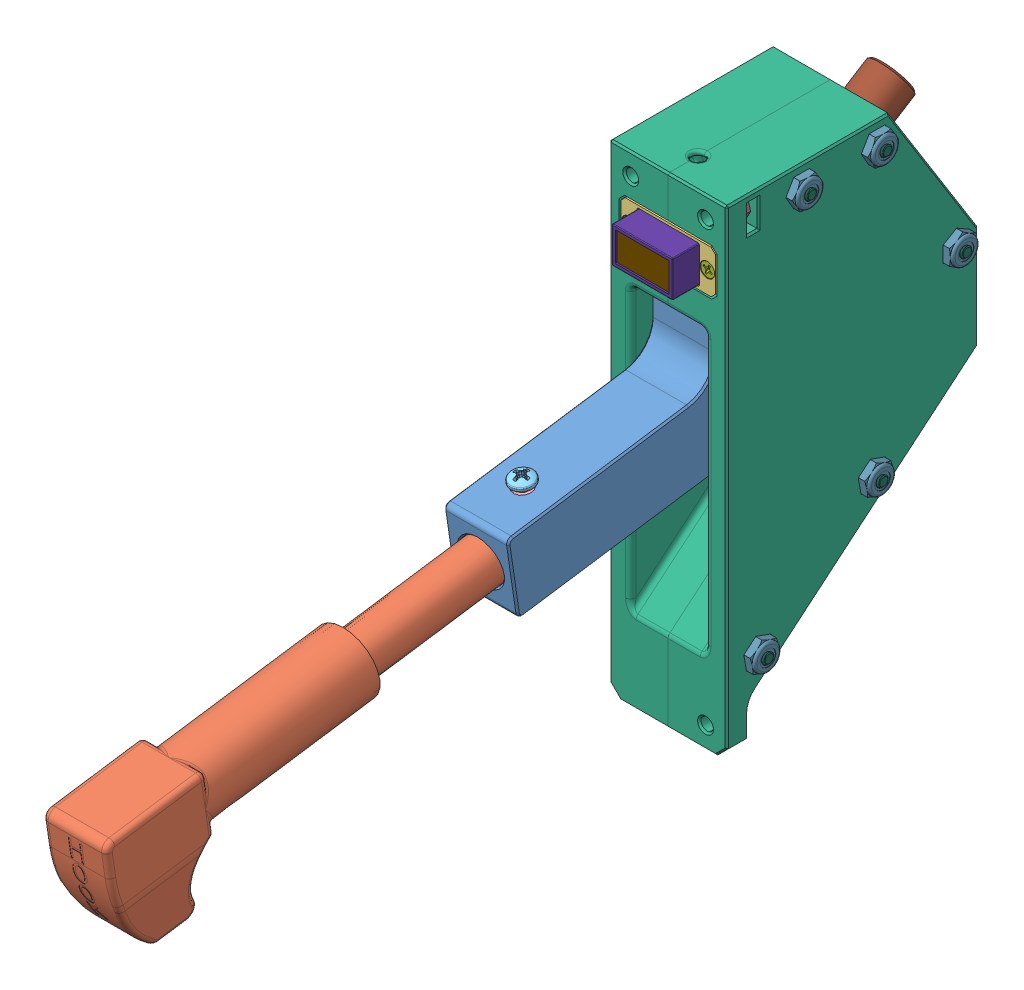
SolidWorks assembly Hook Lever Assembly, configuration UP. Lengths in mm.
Overall size (40.7 142.92 260.87).
49 component instances, 25 part files, 11 mates.
Components (placement in the parent):
- Hook Lever-1: Hook Lever [Default] at (0 -0.2029 9.2115) x (1 0 0) z (0 -0.006159 0.999981) size (22.23 101.03 219.67)
  - Hook Lever Body-1: Hook Lever Body [Default] at origin size (19.05 66.67 99.86)
  - Hook Lever Handle-1: Hook Lever Handle [Default] at (0 20.3447 1.0942) x (1 0 0) z (0 -0.139173 0.990268) size (19.43 38.29 166.69)
  - 6338K411-1: 6338K411 [Default] at (11.1125 50.8 -33.1) x (0 -1 0) z (0 0 -1) size (12.7 6.35 12.7)
  - 6338K411-2: 6338K411 [Default] at (-11.1125 50.8 -33.1) x (0 -1 0) z (0 0 1) size (12.7 6.35 12.7)
  - 93365A130-1: 93365A130 [Default] at (0 26.9745 33.7674) x (1 0 0) z (0 -0.139173 0.990268) size (5.56 3.88 5.56)
  - 91249A144-1: 91249A144 [Default] at (0 21.9439 33.0604) x (1 0 0) z (0 0.990268 0.139173) size (20.88 20.88 23.36)
- Hook Lever Chassis-1: Hook Lever Chassis [Default] at origin size (40.7 142.92 101.62)
  - Hook Lever Chassis Body-1: Hook Lever Chassis Body [Default] at origin size (34.93 142.92 75.16)
  - Hook Lever .25 Shaft -1: Hook Lever .25 Shaft  [Default] at origin size (31.75 6.35 6.35)
  - 93365A120_BRASS HEAT-SET INSERT FOR PLASTICS_4-40-1: 93365A120_BRASS HEAT-SET INSERT FOR PLASTICS_4-40 [93365A120] at (-11.1125 2.6229 -53.39) x (0 1 0) z (0 0 -1) size (4.37 3.82 4.37)
  - 93365A120_BRASS HEAT-SET INSERT FOR PLASTICS_4-40-2: 93365A120_BRASS HEAT-SET INSERT FOR PLASTICS_4-40 [93365A120] at (-11.1125 24.8048 -63.6241) x (0 -1 0) z (0 0 1) size (4.37 3.82 4.37)
  - 7779K52-1: 7779K52 [Default] at (-5.9575 13.7248 -58.4313) x (0 0.642788 -0.766044) z (1 0 0) size (37.8 27.88 10.31)
  - 91249A115-1: 91249A115 [Default] at (-16.6775 2.6447 -53.2386) x (0 -0.642788 0.766044) z (1 0 0) size (23.09 11.07 22.41)
  - 91249A115-2: 91249A115 [Default] at (-16.6775 24.8048 -63.6241) x (0 -0.642788 0.766044) z (1 0 0) size (23.09 11.07 22.41)
  - 84835A14-1: 84835A14 [Default] at (0 68.5051 -51.909) x (1 0 0) z (0 0.848048 0.529919) size (17.48 34.82 17.48)
  - 92141A029-1: 92141A029 [Default] at (-11.1887 50.8 -23.575) x (0 1 0) z (0 0 1) size (15.88 1.45 15.88)
  - 92141A029-2: 92141A029 [Default] at (11.1887 50.8 -23.575) x (0 -1 0) z (0 0 1) size (15.88 1.45 15.88)
  - 91841A007-1: 91841A007 [Default] at (11.1125 -50.8 -6.4691) x (1 0 0) z (0 1 0) size (9.17 3.79 9.17)
  - 91841A007-3: 91841A007 [Default] at (11.1125 79.375 -7.7391) x (0 -1 0) z (1 0 0) size (9.17 3.79 9.17)
  - 91841A007-4: 91841A007 [Default] at (-11.1125 79.375 -7.7391) x (0 -1 0) z (1 0 0) size (9.17 3.79 9.17)
  - 91831A007-1: 91831A007 [Default] at (15.875 -33.7081 -9.4371) x (0 -0.939693 0.34202) z (0 0.34202 0.939693) size (7.94 4.49 9.17)
  - 91831A007-2: 91831A007 [Default] at (15.875 -5.1362 -43.4878) x (0 -0.939693 0.34202) z (0 0.34202 0.939693) size (7.94 4.49 9.17)
  - 91831A007-3: 91831A007 [Default] at (15.875 41.4731 -68.3396) x (0 -0.866025 0.5) z (0 0.5 0.866025) size (7.94 4.49 9.17)
  - 91831A007-4: 91831A007 [Default] at (15.875 79.375 -44.6558) x (0 -1 0) z (0 0 1) size (7.94 4.49 9.17)
  - 91831A007-5: 91831A007 [Default] at (15.875 79.375 -22.225) x (0 -1 0) z (0 0 1) size (7.94 4.49 9.17)
  - 91249A164 - PHS, 6-32 X 1.50, STEEL, BLACK OXIDE-1: 91249A164 - PHS, 6-32 X 1.50, STEEL, BLACK OXIDE [91249A164] at (20.6375 41.4731 -68.3396) x (0 0 1) z (-1 0 0) size (6.86 6.86 40.7)
  - 91249A164 - PHS, 6-32 X 1.50, STEEL, BLACK OXIDE-2: 91249A164 - PHS, 6-32 X 1.50, STEEL, BLACK OXIDE [91249A164] at (20.6375 -5.1362 -43.4878) x (0 0 1) z (-1 0 0) size (6.86 6.86 40.7)
  - 91249A164 - PHS, 6-32 X 1.50, STEEL, BLACK OXIDE-3: 91249A164 - PHS, 6-32 X 1.50, STEEL, BLACK OXIDE [91249A164] at (20.6375 79.375 -44.6558) x (0 0 1) z (-1 0 0) size (6.86 6.86 40.7)
  - 91249A164 - PHS, 6-32 X 1.50, STEEL, BLACK OXIDE-4: 91249A164 - PHS, 6-32 X 1.50, STEEL, BLACK OXIDE [91249A164] at (20.6375 -33.7081 -9.4371) x (0 0 1) z (-1 0 0) size (6.86 6.86 40.7)
  - 91249A164 - PHS, 6-32 X 1.50, STEEL, BLACK OXIDE-5: 91249A164 - PHS, 6-32 X 1.50, STEEL, BLACK OXIDE [91249A164] at (20.6375 79.375 -22.225) x (0 0 1) z (-1 0 0) size (6.86 6.86 40.7)
  - 93365A110_BRASS HEAT-SET INSERT FOR PLASTICS_2-56-1: 93365A110_BRASS HEAT-SET INSERT FOR PLASTICS_2-56 [Default] at (-11.6522 66.675 -3.937) x (1 0 0) z (0 -1 0) size (3.58 3.09 3.58)
  - 93365A110_BRASS HEAT-SET INSERT FOR PLASTICS_2-56-2: 93365A110_BRASS HEAT-SET INSERT FOR PLASTICS_2-56 [Default] at (11.6523 66.675 -3.937) x (0.987351 0.158553 0) z (0.158553 -0.987351 0) size (3.58 3.09 3.58)
- HOOK Indicator-1: HOOK Indicator [Default] at (5.842 54.1655 -0.762) x (0 -1 0) z (0 0 1) size (12.76 28.07 17.75)
  - HOOK Indicator Body-1: HOOK Indicator Body [Default] at (-27.1791 -47.7207 0) size (10.73 18.03 8.45)
  - HOOK Indicator Cover-1: HOOK Indicator Cover [Default] at (-27.1791 -47.7207 7.9375) x (-1 0 0) z (0 0 -1) size (9.21 16.51 0.76)
  - HOOK Indicator Legend-1: HOOK Indicator Legend [Default] at (2.1601 36.0367 7.1755) x (1 0 0) z (0 0 -1) size (9.21 16.51 0.13)
  - HOOK Indicator Diffuser-1: HOOK Indicator Diffuser [Default] at (-27.1791 -47.7207 7.0485) x (-1 0 0) z (0 0 -1) size (9.21 16.51 0.13)
  - HOOK Indicator Mount Plate-1: HOOK Indicator Mount Plate [Default] at (-27.1791 -47.7207 0) x (-1 0 0) z (0 0 -1) size (12.76 28.07 3.94)
  - CR-104 - HOLDER, LED, 3mm-1: CR-104 - HOLDER, LED, 3mm [Default] at (-12.7 -11.2846 0.381) x (0 -1 0) z (0 0 -1) size (6.1 6.1 7.11)
    - C-104-1: C-104 [Default] at origin size (5.28 5.28 5.34)
    - R-104-1: R-104 [Default] at (0 0 3.556) size (6.1 6.1 3.56)
  - LTW-420D7-1: LTW-420D7 [Default] at (-12.7 -11.2846 -4.2051) x (-1 0 0) z (0 1 0) size (3.4 10.4 3.8)
  - CR-104 - HOLDER, LED, 3mm-2: CR-104 - HOLDER, LED, 3mm [Default] at (-12.7 -0.7804 0.381) x (0 -1 0) z (0 0 -1) size (6.1 6.1 7.11)
    - C-104-1: C-104 [Default] at origin size (5.28 5.28 5.34)
    - R-104-1: R-104 [Default] at (0 0 3.556) size (6.1 6.1 3.56)
  - LTW-420D7-2: LTW-420D7 [Default] at (-12.7 -0.7804 -4.2051) x (-1 0 0) z (0 1 0) size (3.4 10.4 3.8)
- 90471A130 - SCREW, 100 DEG CSK, 2-56 x .375, STEEL-1: 90471A130 - SCREW, 100 DEG CSK, 2-56 x .375, STEEL [90471A130] at (-11.6522 66.675 -1.0464) x (-0.838675 0.544632 0) z (0 0 1) size (4.11 4.11 9.71)
- 90471A130 - SCREW, 100 DEG CSK, 2-56 x .375, STEEL-2: 90471A130 - SCREW, 100 DEG CSK, 2-56 x .375, STEEL [90471A130] at (11.6523 66.675 -1.0464) x (-0.914419 0.404768 0) z (0 0 1) size (4.11 4.11 9.71)
Mates (geometry in assembly coordinates):
- Concentric1: concentric anti-aligned: cylinder of Hook Lever-1/6338K411-2 through (-4.7625 50.8 -23.575) axis (-1 0 0) radius 3.2004; cylinder of Hook Lever Chassis-1/Hook Lever .25 Shaft -1 through (0 50.8 -23.575) axis (1 0 0) radius 3.175
- Width1: width anti-aligned: plane of Hook Lever-1/6338K411-2 through (-11.1125 50.8 -23.575) normal (-1 0 0); plane of Hook Lever Chassis-1/Hook Lever Chassis Body-1 through (11.1125 50.8 -23.575) normal (1 0 0); plane of Hook Lever-1/6338K411-1 through (-11.1125 14.2875 -37.3448) normal (1 0 0); plane of Hook Lever Chassis-1/Hook Lever Chassis Body-1 through (11.1125 14.2875 -37.3448) normal (-1 0 0)
- Parallel4: parallel anti-aligned: plane of Hook Lever-1 through (0 38.6367 -52.9448) normal (0 -0.529919 0.848048); plane of Hook Lever Chassis-1/Hook Lever Chassis Body-1 through (0 43.2939 -74.6896) normal (0 0.529919 -0.848048)
- Parallel5: parallel anti-aligned: plane of Hook Lever-1 through (0 3.5965 -45.5912) normal (0 -0.069163 0.997605); plane of Hook Lever Chassis-1/Hook Lever Chassis Body-1 through (0 43.2939 -74.6896) normal (0 0.529919 -0.848048)
- Width2: width anti-aligned: plane of Hook Lever Chassis-1/Hook Lever Chassis Body-1 through (-17.4625 14.2875 -37.3448) normal (-1 0 0); plane of HOOK Indicator-1/HOOK Indicator Body-1 through (17.4625 14.2875 -37.3448) normal (1 0 0); plane of Hook Lever Chassis-1/Hook Lever Chassis Body-1 through (9.017 72.0408 7.1755) normal (1 0 0); plane of HOOK Indicator-1/HOOK Indicator Body-1 through (-9.017 72.0408 7.1755) normal (-1 0 0)
- Coincident2: coincident aligned: plane of Hook Lever Chassis-1/Hook Lever Chassis Body-1 through (0 -33.3375 0) normal (0 0 1); plane of HOOK Indicator-1/HOOK Indicator Mount Plate-1 through (-41.8787 81.3446 0) normal (0 0 1)
- Distance1: distance = 12.6683 mm aligned: plane of HOOK Indicator-1/HOOK Indicator Mount Plate-1 through (-14.0335 73.0568 0) normal (0 1 0); plane of Hook Lever Chassis-1/Hook Lever Chassis Body-1 through (0 85.725 -48.1757) normal (0 1 0)
- Concentric2: concentric aligned: cone of HOOK Indicator-1/HOOK Indicator Mount Plate-1 through (-11.6522 66.675 0) axis (0 0 -1); cone of 90471A130 - SCREW, 100 DEG CSK, 2-56 x .375, STEEL-1 through (-11.6522 66.675 -0.1066) axis (0 0 -1)
- Coincident3: coincident aligned: cone of HOOK Indicator-1/HOOK Indicator Mount Plate-1 through (-11.6522 66.675 0) axis (0 0 -1); cone of 90471A130 - SCREW, 100 DEG CSK, 2-56 x .375, STEEL-1 through (-11.6522 66.675 -0.1066) axis (0 0 -1)
- Concentric3: concentric aligned: cone of HOOK Indicator-1/HOOK Indicator Mount Plate-1 through (11.6523 66.675 0) axis (0 0 -1); cone of 90471A130 - SCREW, 100 DEG CSK, 2-56 x .375, STEEL-2 through (11.6523 66.675 -0.1066) axis (0 0 -1)
- Coincident4: coincident aligned: cone of HOOK Indicator-1/HOOK Indicator Mount Plate-1 through (11.6523 66.675 0) axis (0 0 -1); cone of 90471A130 - SCREW, 100 DEG CSK, 2-56 x .375, STEEL-2 through (11.6523 66.675 -0.1066) axis (0 0 -1)
